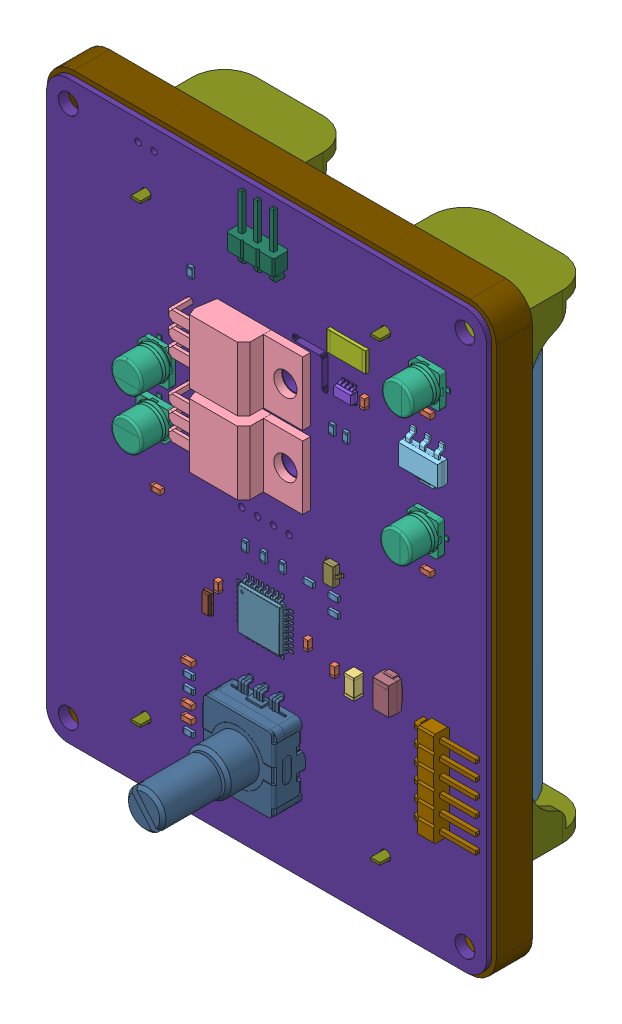
SolidWorks assembly SimpleServoTester, configuration Default. Lengths in mm.
Overall size (72.2 94 44.48).
87 component instances, 19 part files, 7 mates.
Components (placement in the parent):
- SimpleServoTester.step-1: SimpleServoTester.step [Default] at origin size (70.79 92.5 42.61)
  - R_0603_1608Metric.step-1: R_0603_1608Metric.step [Default] at (106 -118.5 1.65) size (1.6 0.8 0.45)
    - SOLID.step-1: SOLID.step [Default] at origin size (1.6 0.8 0.45)
  - C_0603_1608Metric.step-1: C_0603_1608Metric.step [Default] at (110.8 -101.6 1.65) x (0 1 0) z (0 0 1) size (1.6 0.8 0.8)
    - SOLID-0.step-1: SOLID-0.step [Default] at origin size (1.6 0.8 0.8)
  - L_1206_3216Metric.step-1: L_1206_3216Metric.step [Default] at (133 -104 1.65) x (0 1 0) z (0 0 1) size (3.2 1.6 1.6)
    - SOLID-1.step-1: SOLID-1.step [Default] at origin size (3.2 1.6 1.6)
  - TO-220-3_Horizontal_TabDown.step-1: TO-220-3_Horizontal_TabDown.step [Default] at (105.75 -64.71 1.65) x (0 -1 0) z (0 0 1) size (10.25 19.74 10.78)
    - SOLID-2.step-1: SOLID-2.step [Default] at origin size (10.25 19.74 10.78)
  - R_0603_1608Metric.step-2: R_0603_1608Metric.step [Default] at (129.25 -94 1.65) size (1.6 0.8 0.45)
    - SOLID.step-1: SOLID.step [Default] at origin size (1.6 0.8 0.45)
  - SOT-223.step-1: SOT-223.step [Default] at (144.19 -67.5 1.65) x (0 -1 0) z (0 0 1) size (7 6.5 1.7)
    - SOLID-3.step-1: SOLID-3.step [Default] at origin size (7 6.5 1.7)
  - CP_Elec_5x5.4.step-1: CP_Elec_5x5.4.step [Default] at (101 -75 1.65) x (0 -1 0) z (0 0 1) size (6.99 6.83 5.4)
    - SOLID-4.step-1: SOLID-4.step [Default] at origin size (6.99 6.83 5.4)
  - C_0603_1608Metric.step-2: C_0603_1608Metric.step [Default] at (129.5 -104 1.65) x (0 1 0) z (0 0 1) size (1.6 0.8 0.8)
    - SOLID-0.step-1: SOLID-0.step [Default] at origin size (1.6 0.8 0.8)
  - R_2512_6332Metric.step-1: R_2512_6332Metric.step [Default] at (131.55 -58.525 1.65) size (6.3 3.2 0.6)
    - SOLID-5.step-1: SOLID-5.step [Default] at origin size (6.3 3.2 0.6)
  - R_0603_1608Metric.step-3: R_0603_1608Metric.step [Default] at (125.25 -94 1.65) size (1.6 0.8 0.45)
    - SOLID.step-1: SOLID.step [Default] at origin size (1.6 0.8 0.45)
  - R_0603_1608Metric.step-4: R_0603_1608Metric.step [Default] at (121 -94 1.65) x (0 -1 0) z (0 0 1) size (1.6 0.8 0.45)
    - SOLID.step-1: SOLID.step [Default] at origin size (1.6 0.8 0.45)
  - R_0603_1608Metric.step-5: R_0603_1608Metric.step [Default] at (131.2 -70.775 1.65) x (0 -1 0) z (0 0 1) size (1.6 0.8 0.45)
    - SOLID.step-1: SOLID.step [Default] at origin size (1.6 0.8 0.45)
  - SOT-23-8.step-1: SOT-23-8.step [Default] at (131.525 -64.3875 1.65) x (0 1 0) z (0 0 1) size (2.8 2.9 1.2)
    - SOLID-6.step-1: SOLID-6.step [Default] at origin size (2.8 2.9 1.2)
  - C_0603_1608Metric.step-3: C_0603_1608Metric.step [Default] at (134.3 -64.3 1.65) x (0 -1 0) z (0 0 1) size (1.6 0.8 0.8)
    - SOLID-0.step-1: SOLID-0.step [Default] at origin size (1.6 0.8 0.8)
  - R_0603_1608Metric.step-6: R_0603_1608Metric.step [Default] at (129 -70.775 1.65) x (0 -1 0) z (0 0 1) size (1.6 0.8 0.45)
    - SOLID.step-1: SOLID.step [Default] at origin size (1.6 0.8 0.45)
  - PinHeader_1x06_P2.54mm_Horizontal.step-1: PinHeader_1x06_P2.54mm_Horizontal.step [Default] at (143.5 -104.25 1.65) size (10.36 15.24 5.54)
    - SOLID-7.step-1: SOLID-7.step [Default] at origin size (10.36 15.24 5.54)
  - EC11-THT-15R-black.step-1: EC11-THT-15R-black.step [Default] at (118 -119.75 1.65) x (-1 0 0) z (0 0 1) size (12.4 14.95 23)
    - COMPOUND.step-1: COMPOUND.step [Default] at origin size (12.4 14.95 23)
  - C_0603_1608Metric.step-4: C_0603_1608Metric.step [Default] at (101 -93 1.65) x (-1 0 0) z (0 0 1) size (1.6 0.8 0.8)
    - SOLID-0.step-1: SOLID-0.step [Default] at origin size (1.6 0.8 0.8)
  - CP_Elec_5x5.4.step-2: CP_Elec_5x5.4.step [Default] at (144.24 -77 1.65) size (6.99 6.83 5.4)
    - SOLID-4.step-1: SOLID-4.step [Default] at origin size (6.99 6.83 5.4)
  - R_0603_1608Metric.step-7: R_0603_1608Metric.step [Default] at (106.25 -60.25 1.65) x (0 1 0) z (0 0 1) size (1.6 0.8 0.45)
    - SOLID.step-1: SOLID.step [Default] at origin size (1.6 0.8 0.45)
  - C_0603_1608Metric.step-5: C_0603_1608Metric.step [Default] at (125.2 -102.45 1.65) x (0 1 0) z (0 0 1) size (1.6 0.8 0.8)
    - SOLID-0.step-1: SOLID-0.step [Default] at origin size (1.6 0.8 0.8)
  - CSTCE16M0V53-R0.step-1: CSTCE16M0V53-R0.step [Default] at (108.35 -103.3 1.65) x (0 1 0) z (0 0 1) size (3.2 1.3 0.7)
    - SOLID-8.step-1: SOLID-8.step [Default] at origin size (3.2 1.3 0.7)
  - SOT23-3.step-1: SOT23-3.step [Default] at (129.25 -90.5 1.65) x (-1 0 0) z (0 0 1) size (2.84 3.01 1.19)
    - COMPOUND-9.step-1: COMPOUND-9.step [Default] at origin size (2.84 3.01 1.19)
  - R_0603_1608Metric.step-8: R_0603_1608Metric.step [Default] at (106 -124.5 1.65) x (-1 0 0) z (0 0 1) size (1.6 0.8 0.45)
    - SOLID.step-1: SOLID.step [Default] at origin size (1.6 0.8 0.45)
  - C_0603_1608Metric.step-6: C_0603_1608Metric.step [Default] at (106 -122.5 1.65) x (-1 0 0) z (0 0 1) size (1.6 0.8 0.8)
    - SOLID-0.step-1: SOLID-0.step [Default] at origin size (1.6 0.8 0.8)
  - R_0603_1608Metric.step-9: R_0603_1608Metric.step [Default] at (129.25 -96.3 1.65) x (-1 0 0) z (0 0 1) size (1.6 0.8 0.45)
    - SOLID.step-1: SOLID.step [Default] at origin size (1.6 0.8 0.45)
  - CP_Elec_5x5.4.step-3: CP_Elec_5x5.4.step [Default] at (101 -83.15 1.65) x (0 1 0) z (0 0 1) size (6.99 6.83 5.4)
    - SOLID-4.step-1: SOLID-4.step [Default] at origin size (6.99 6.83 5.4)
  - C_0603_1608Metric.step-7: C_0603_1608Metric.step [Default] at (144.415 -82.75 1.65) size (1.6 0.8 0.8)
    - SOLID-0.step-1: SOLID-0.step [Default] at origin size (1.6 0.8 0.8)
  - D_SMA.step-1: D_SMA.step [Default] at (138.75 -102.25 1.65) x (0 -1 0) z (0 0 1) size (5 2.7 2.22)
    - SOLID-10.step-1: SOLID-10.step [Default] at origin size (5 2.7 2.22)
  - TO-220-3_Horizontal_TabDown.step-2: TO-220-3_Horizontal_TabDown.step [Default] at (105.75 -76.41 1.65) x (0 -1 0) z (0 0 1) size (10.25 19.74 10.78)
    - SOLID-2.step-1: SOLID-2.step [Default] at origin size (10.25 19.74 10.78)
  - C_0603_1608Metric.step-8: C_0603_1608Metric.step [Default] at (106 -114.5 1.65) size (1.6 0.8 0.8)
    - SOLID-0.step-1: SOLID-0.step [Default] at origin size (1.6 0.8 0.8)
  - R_0603_1608Metric.step-10: R_0603_1608Metric.step [Default] at (118 -94 1.65) x (0 -1 0) z (0 0 1) size (1.6 0.8 0.45)
    - SOLID.step-1: SOLID.step [Default] at origin size (1.6 0.8 0.45)
  - C_0603_1608Metric.step-9: C_0603_1608Metric.step [Default] at (144.45 -60.75 1.65) size (1.6 0.8 0.8)
    - SOLID-0.step-1: SOLID-0.step [Default] at origin size (1.6 0.8 0.8)
  - C_0603_1608Metric.step-10: C_0603_1608Metric.step [Default] at (106 -120.5 1.65) x (-1 0 0) z (0 0 1) size (1.6 0.8 0.8)
    - SOLID-0.step-1: SOLID-0.step [Default] at origin size (1.6 0.8 0.8)
  - TQFP-32_7x7mm_P0.8mm.step-1: TQFP-32_7x7mm_P0.8mm.step [Default] at (118 -102.45 1.65) size (9 9 1.1)
    - SOLID-11.step-1: SOLID-11.step [Default] at origin size (9 9 1.1)
  - CP_Elec_5x5.4.step-4: CP_Elec_5x5.4.step [Default] at (144.5 -56.25 1.65) size (6.99 6.83 5.4)
    - SOLID-4.step-1: SOLID-4.step [Default] at origin size (6.99 6.83 5.4)
  - R_0603_1608Metric.step-11: R_0603_1608Metric.step [Default] at (115 -94 1.65) x (0 -1 0) z (0 0 1) size (1.6 0.8 0.45)
    - SOLID.step-1: SOLID.step [Default] at origin size (1.6 0.8 0.45)
  - PinHeader_1x03_P2.54mm_Horizontal.step-1: PinHeader_1x03_P2.54mm_Horizontal.step [Default] at (115.475 -53.625 1.65) x (0 1 0) z (0 0 1) size (10.36 7.62 5.54)
    - SOLID-12.step-1: SOLID-12.step [Default] at origin size (10.36 7.62 5.54)
  - R_0603_1608Metric.step-12: R_0603_1608Metric.step [Default] at (106 -116.5 1.65) size (1.6 0.8 0.45)
    - SOLID.step-1: SOLID.step [Default] at origin size (1.6 0.8 0.45)
  - BK-18650-PC2.step-1: BK-18650-PC2.step [Default] at (98.75 -89.75 -0.05) x (0 -1 0) z (1 0 0) size (76.96 24.71 21.02)
    - SOLID-13.step-1: SOLID-13.step [Default] at origin size (76.96 24.71 21.02)
  - BK-18650-PC2.step-2: BK-18650-PC2.step [Default] at (137.25 -89.7 -0.05) x (0 1 0) z (-1 0 0) size (76.96 24.71 21.02)
    - SOLID-13.step-1: SOLID-13.step [Default] at origin size (76.96 24.71 21.02)
  - SimpleServoTester PCB.step-1: SimpleServoTester PCB.step [Default] at origin size (70.75 92.5 1.6)
- Back-1: Back [Default] at (118.15 -89.75 0.8) x (-1 0 0) z (0 1 0) size (72.2 22.8 94)
- 18650 Li-Ion.step-1: 18650 Li-Ion.step [Default] at (98.8178 -122.4211 -10.9804) x (0.988922 0 -0.148434) z (0.148434 0 0.988922) size (18 65 18)
- 18650 Li-Ion.step-2: 18650 Li-Ion.step [Default] at (137.1822 -57.3865 -10.9804) x (0.515791 0 -0.856715) z (-0.856715 0 -0.515791) size (18 65 18)
Mates (geometry in assembly coordinates):
- Coincident1: coincident anti-aligned: line of SimpleServoTester.step-1/SimpleServoTester PCB.step-1 through (63.75 86.25 -43.5) axis (0 1 0); line of Back-1 through (150 -43.5 0) axis (-1 0 0)
- Coincident2: coincident anti-aligned: line of SimpleServoTester.step-1/SimpleServoTester PCB.step-1 through (63.75 150 -136) axis (0 -1 0); line of Back-1 through (86.3 -136 0) axis (1 0 0)
- Coincident3: coincident anti-aligned: line of SimpleServoTester.step-1/SimpleServoTester PCB.step-1 through (85.5 153.5 -47) axis (0 0 -1); line of Back-1 through (153.5 -132.5 0) axis (0 1 0)
- Tangent1: tangent anti-aligned: plane of SimpleServoTester.step-1/BK-18650-PC2.step-1/SOLID-13.step-1 through (98.75 -89.75 -1.9804) normal (0 0 -1); cylinder of 18650 Li-Ion.step-1 through (98.8178 -87.9547 -10.9804) axis (0 1 0) radius 9
- Tangent2: tangent anti-aligned: plane of SimpleServoTester.step-1/BK-18650-PC2.step-1/SOLID-13.step-1 through (107.8178 -126.5165 -1.9804) normal (-1 0 0); cylinder of 18650 Li-Ion.step-1 through (98.8178 -87.9547 -10.9804) axis (0 1 0) radius 9
- Tangent3: tangent anti-aligned: plane of SimpleServoTester.step-1/BK-18650-PC2.step-2/SOLID-13.step-1 through (137.25 -89.7 -1.9804) normal (0 0 -1); cylinder of 18650 Li-Ion.step-2 through (137.1822 -91.8528 -10.9804) axis (0 -1 0) radius 9
- Tangent4: tangent anti-aligned: plane of SimpleServoTester.step-1/BK-18650-PC2.step-2/SOLID-13.step-1 through (128.1822 -52.9335 -1.9804) normal (1 0 0); cylinder of 18650 Li-Ion.step-2 through (137.1822 -91.8528 -10.9804) axis (0 -1 0) radius 9
